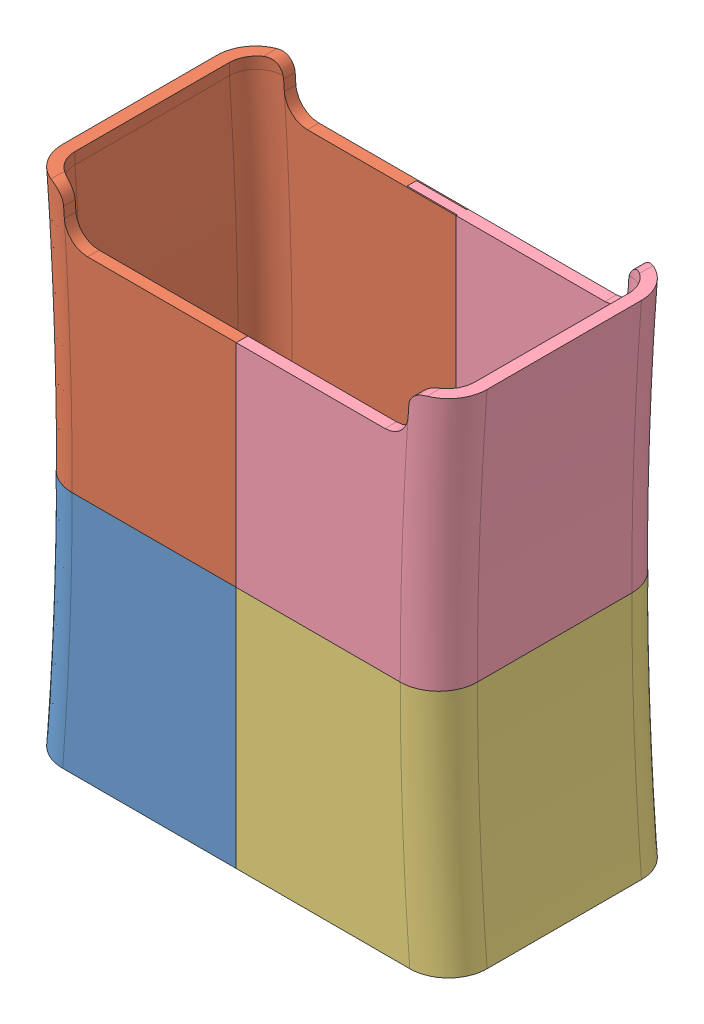
SolidWorks assembly FTOO Assembly, configuration Default. Lengths in mm.
Overall size (564.76 650 305.68).
4 component instances, 4 part files, 9 mates.
Components (placement in the parent):
- LEFT D-1: LEFT D [Default] at (143.4922 6.8924 153.0272) size (282.38 315.43 305.66)
- LEFT U-1: LEFT U [Default] at (143.497 6.8924 153.0272) size (282.3 409.57 305.64)
- RIGHT D-1: RIGHT D [Default] at (143.497 6.8924 153.0272) size (282.38 315.43 305.66)
- RIGHT U-1: RIGHT U [Default] at (143.497 6.8924 153.0272) size (347.3 409.57 305.64)
Mates (geometry in assembly coordinates):
- Coincident1: coincident aligned: plane of LEFT D-1 through (81.207 247.3254 388.0272) normal (0 -1 0); plane of LEFT U-1 through (143.497 247.3254 153.0272) normal (0 -1 0)
- Coincident2: coincident anti-aligned: plane of LEFT D-1 through (56.207 230.3254 153.0272) normal (-1 0 0); plane of LEFT U-1 through (56.207 247.3254 153.0272) normal (1 0 0)
- Coincident3: coincident anti-aligned: plane of LEFT D-1 through (-119.0078 327.8574 438.0272) normal (0 0 -1); plane of LEFT U-1 through (143.497 247.3254 438.0272) normal (0 0 1)
- Coincident4: coincident anti-aligned: plane of RIGHT D-1 through (230.787 177.3254 184.6447) normal (1 0 0); plane of RIGHT U-1 through (230.787 247.3254 184.6447) normal (-1 0 0)
- Coincident5: coincident aligned: plane of RIGHT D-1 through (143.497 247.3254 419.6447) normal (0 -1 0); plane of RIGHT U-1 through (143.497 247.3254 184.6447) normal (0 -1 0)
- Coincident6: coincident anti-aligned: plane of RIGHT D-1 through (143.497 177.3254 439.6447) normal (0 0 1); plane of RIGHT U-1 through (143.497 247.3254 439.6447) normal (0 0 -1)
- Coincident10: coincident anti-aligned: plane of LEFT U-1 through (78.497 586.8924 154.5272) normal (1 0 0); plane of RIGHT U-1 through (78.497 586.8924 186.1447) normal (-1 0 0)
- Coincident11: coincident anti-aligned: plane of LEFT U-1 through (143.497 576.8924 153.0272) normal (0 1 0); plane of RIGHT U-1 through (143.497 576.8924 184.6447) normal (0 -1 0)
- Coincident13: coincident anti-aligned: plane of LEFT U-1 through (144.6329 586.8924 154.5272) normal (0 0 1); plane of RIGHT U-1 through (143.497 586.8924 154.5272) normal (0 0 -1)
